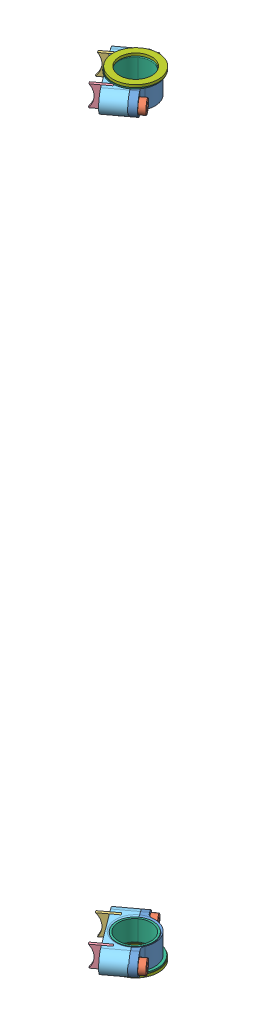
SolidWorks assembly PUTM-S-SR-RB-Mounting, configuration Domyślna. Lengths in mm.
Overall size (57.13 597.42 61.59).
22 component instances, 8 part files, 12 mates.
Components (placement in the parent):
- PUTM-S-SR-RB_bearing_mount_assembly-1: PUTM-S-SR-RB_bearing_mount_assembly [Domyślna] at (-1341.5433 287.7118 402.548) x (0.802303 0 -0.596917) z (0 -1 0) size (29.5 53.3 16)
  - PUTM-S-SR-RB-bearing_mount-1: PUTM-S-SR-RB-bearing_mount [Domyślna] at (-0.5 -47.6728 -8) size (15.5 53.3 16)
  - PUTM-S-SR-RB-bearing_mount_low-1: PUTM-S-SR-RB-bearing_mount_low [Domyślna] at (0 -47.6728 0) x (0 1 0) z (0 0 -1) (suppressed, hidden)
  - PUTM-S-SR-RB-Bolt-2: PUTM-S-SR-RB-Bolt [Domyślna] at (9.5 -69.0728 0) x (0 -0.0195 -0.99981) z (0 -0.99981 0.0195) size (10 24 10)
- PUTM-S-SR-RB-laser1-1: PUTM-S-SR-RB-laser1 [Domyślna] at (-1436.4628 288.3541 396.2936) x (0.802303 0 -0.596917) z (0.596917 0 0.802303) size (14.24 16 2)
- PUTM-S-SR-RB-laser2-1: PUTM-S-SR-RB-laser2 [Domyślna] at (-1364.506 295.7022 380.1498) x (0 -1 0) z (-0.596917 0 -0.802303) size (16 13.75 2)
- PUTM-S-SR-RB-bearing_mount_low_v2-1: PUTM-S-SR-RB-bearing_mount_low_v2 [Domyślna] at (-1370.0451 287.7022 364.3283) x (-0.596917 0 -0.802303) z (0 -1 0) size (53.3 16.5 16)
- PUTM-S-SR-RB-PCMF 252816.5 [SKF]-1: PUTM-S-SR-RB-PCMF 252816.5 [SKF] [Domyślna] at (-1370.4012 296.7084 364.5985) x (0 -1 0) z (-0.802303 0 0.596917) size (16.5 35 17.5)
- PUTM-S-SR-RB-bearing_end-1: PUTM-S-SR-RB-bearing_end [Domyślna] at (-1370 298.7118 364.3) x (0 -1 0) z (-0.524721 0 -0.851274) size (2 35 35)
- PUTM-S-SR-RB-Bolt-2: PUTM-S-SR-RB-Bolt [Domyślna] at (-1349.6041 287.7118 375.7986) x (-0.533972 0.446969 -0.7177) z (-0.266803 -0.89455 -0.358604) size (10 24 10)
- PUTM-S-SR-RB-PCMF 252816.5 [SKF]-2: PUTM-S-SR-RB-PCMF 252816.5 [SKF] [Domyślna] at (-1370.4012 296.7118 364.5985) x (0 -1 0) z (0.802303 0 -0.596917) size (16.5 35 17.5)
- PUTM-S-SR-RB-laser2-2: PUTM-S-SR-RB-laser2 [Domyślna] at (-1365.6998 -295.7022 378.5452) x (0 1 0) z (0.596917 0 0.802303) size (16 13.75 2)
- PUTM-S-SR-RB-Bolt-3: PUTM-S-SR-RB-Bolt [Domyślna] at (-1349.6041 -287.7118 375.7986) x (-0.533972 -0.446969 -0.7177) z (0.266803 -0.89455 0.358604) size (10 24 10)
- PUTM-S-SR-RB-bearing_mount_low_v2-2: PUTM-S-SR-RB-bearing_mount_low_v2 [Domyślna] at (-1370.0451 -287.7022 364.3283) x (0.596917 0 0.802303) z (0 1 0) size (53.3 16.5 16)
- PUTM-S-SR-RB-laser1-2: PUTM-S-SR-RB-laser1 [Domyślna] at (-1437.6566 -288.3541 394.689) x (0.802303 0 -0.596917) z (-0.596917 0 -0.802303) size (14.24 16 2)
- PUTM-S-SR-RB_bearing_mount_assembly-2: PUTM-S-SR-RB_bearing_mount_assembly [Domyślna] at (-1341.5433 -287.7118 402.548) x (0.802303 0 -0.596917) z (0 -1 0) size (29.5 53.3 16)
  - PUTM-S-SR-RB-bearing_mount-1: PUTM-S-SR-RB-bearing_mount [Domyślna] at (-0.5 -47.6728 -8) size (15.5 53.3 16)
  - PUTM-S-SR-RB-bearing_mount_low-1: PUTM-S-SR-RB-bearing_mount_low [Domyślna] at (0 -47.6728 0) x (0 1 0) z (0 0 -1) (suppressed, hidden)
  - PUTM-S-SR-RB-Bolt-2: PUTM-S-SR-RB-Bolt [Domyślna] at (9.5 -69.0728 0) x (0 -0.0195 -0.99981) z (0 -0.99981 0.0195) size (10 24 10)
- PUTM-S-SR-RB-PCMF 252816.5 [SKF]-3: PUTM-S-SR-RB-PCMF 252816.5 [SKF] [Domyślna] at (-1370.4012 -296.7118 364.5985) x (0 1 0) z (0.802303 0 -0.596917) size (16.5 35 17.5)
- PUTM-S-SR-RB-bearing_end-2: PUTM-S-SR-RB-bearing_end [Domyślna] at (-1370 -298.7118 364.3) x (0 1 0) z (0.524721 0 0.851274) size (2 35 35)
- PUTM-S-SR-RB-PCMF 252816.5 [SKF]-4: PUTM-S-SR-RB-PCMF 252816.5 [SKF] [Domyślna] at (-1370.4012 -296.7084 364.5985) x (0 1 0) z (-0.802303 0 0.596917) size (16.5 35 17.5)
Mates (geometry in assembly coordinates):
- Wspólnie78: coincident aligned: plane of PUTM-S-SR-RB-PCMF 252816.5 [SKF]-2 through (-1362.3428 295.7118 375.4295) normal (-0.802303 0 0.596917); plane of PUTM-S-SR-RB_bearing_mount_assembly-1/PUTM-S-SR-RB-bearing_mount-1 through (-1361.1489 279.7118 377.0342) normal (-0.802303 0 0.596917)
- Wspólnie92: coincident aligned: plane of PUTM-S-SR-RB-PCMF 252816.5 [SKF]-2 through (-1359.9551 295.7118 378.6388) normal (0 -1 0); circle of PUTM-S-SR-RB_bearing_mount_assembly-1/PUTM-S-SR-RB-bearing_mount-1
- Koncentryczne9: concentric aligned: cylinder of PUTM-S-SR-RB_bearing_mount_assembly-1/PUTM-S-SR-RB-bearing_mount-1 through (-1353.2145 287.7118 378.4847) axis (-0.802303 0 0.596917) radius 3; cylinder of PUTM-S-SR-RB-Bolt-2 through (-1349.6041 287.7118 375.7986) axis (-0.802303 0 0.596917) radius 3
- Wspólnie26: coincident anti-aligned: plane of PUTM-S-SR-RB_bearing_mount_assembly-1/PUTM-S-SR-RB-bearing_mount-1 through (-1365.9885 295.7118 361.3154) normal (0.802303 0 -0.596917); plane of PUTM-S-SR-RB-Bolt-2 through (-1355.8843 289.9467 374.8962) normal (-0.802303 0 0.596917)
- Wspólnie76: coincident anti-aligned: plane of PUTM-S-SR-RB-bearing_mount_low_v2-1 through (-1378.402 295.7022 353.0961) normal (-0.596917 0 -0.802303); plane of PUTM-S-SR-RB-laser1-1 through (-1436.4628 288.3541 396.2936) normal (0.596917 0 0.802303)
- Wspólnie86: coincident anti-aligned: plane of PUTM-S-SR-RB-laser1-1 through (-1389.4096 288.3541 355.0538) normal (0.802303 0 -0.596917); plane of PUTM-S-SR-RB-bearing_mount_low_v2-1 through (-1378.0681 295.7022 370.2975) normal (-0.802303 0 0.596917)
- Wspólnie87: coincident aligned: plane of PUTM-S-SR-RB-laser1-1 through (-1437.6566 279.7022 394.689) normal (0 -1 0); plane of PUTM-S-SR-RB-bearing_mount_low_v2-1 through (-1370.0451 279.7022 364.3283) normal (0 -1 0)
- Wspólnie93: coincident anti-aligned: plane of PUTM-S-SR-RB-laser2-1 through (-1365.6998 295.7022 378.5452) normal (-0.596917 0 -0.802303); plane of PUTM-S-SR-RB-bearing_mount_low_v2-1 through (-1361.6883 295.7022 375.5606) normal (0.596917 0 0.802303)
- Wspólnie94: coincident aligned: plane of PUTM-S-SR-RB-laser2-1 through (-1365.6998 279.7022 378.5452) normal (0 -1 0); plane of PUTM-S-SR-RB-bearing_mount_low_v2-1 through (-1370.0451 279.7022 364.3283) normal (0 -1 0)
- Wspólnie95: coincident anti-aligned: plane of PUTM-S-SR-RB-laser2-1 through (-1366.7267 295.7022 385.5413) normal (0.802303 0 -0.596917); plane of PUTM-S-SR-RB-bearing_mount_low_v2-1 through (-1378.0681 295.7022 370.2975) normal (-0.802303 0 0.596917)
- Wspólnie79: coincident anti-aligned: plane of PUTM-S-SR-RB-PCMF 252816.5 [SKF]-2 through (-1378.4595 295.7118 353.7674) normal (-0.802303 0 0.596917); plane of PUTM-S-SR-RB-PCMF 252816.5 [SKF]-1 through (-1378.4595 295.7084 353.7674) normal (0.802303 0 -0.596917)
- Wspólnie96: coincident anti-aligned: plane of PUTM-S-SR-RB-PCMF 252816.5 [SKF]-2 through (-1362.3428 296.7118 375.4295) normal (0 1 0); plane of PUTM-S-SR-RB-bearing_end-1 through (-1370 296.7118 364.3) normal (0 -1 0)
